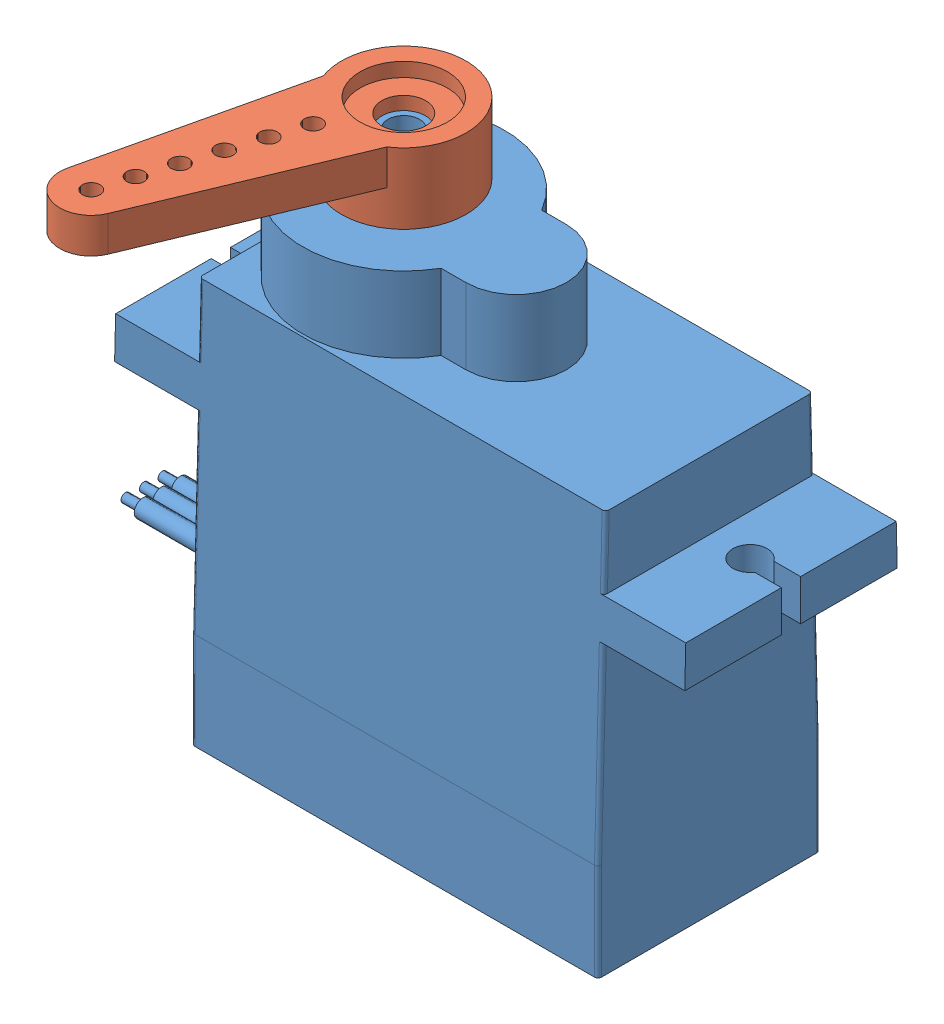
SolidWorks assembly Tower Pro 9g Micro Servo SG90, configuration Default. Lengths in mm.
Overall size (36.67 31.5 22.48).
2 component instances, 2 part files, 2 mates.
Components (placement in the parent):
- Tower Pro 9g Micro Servo SG90-1: Tower Pro 9g Micro Servo SG90 [Default] at origin size (36.67 29.95 12.59)
- SG90 plastic Horn-1: SG90 plastic Horn [Default] at (-1.405 13.16 0) x (-0.305426 0 0.952216) z (-0.952216 0 -0.305426) size (19.4 4 7.07)
Mates (geometry in assembly coordinates):
- Coincident5: coincident anti-aligned: circle of Tower Pro 9g Micro Servo SG90-1; plane of SG90 plastic Horn-1 through (-1.7853 13.61 1.1855) normal (0 -1 0)
- Concentric2: concentric aligned: cylinder of Tower Pro 9g Micro Servo SG90-1 through (-1.405 9.66 0) axis (0 1 0) radius 2.3; cylinder of SG90 plastic Horn-1 through (-1.405 68.16 0) axis (0 1 0) radius 3.535
